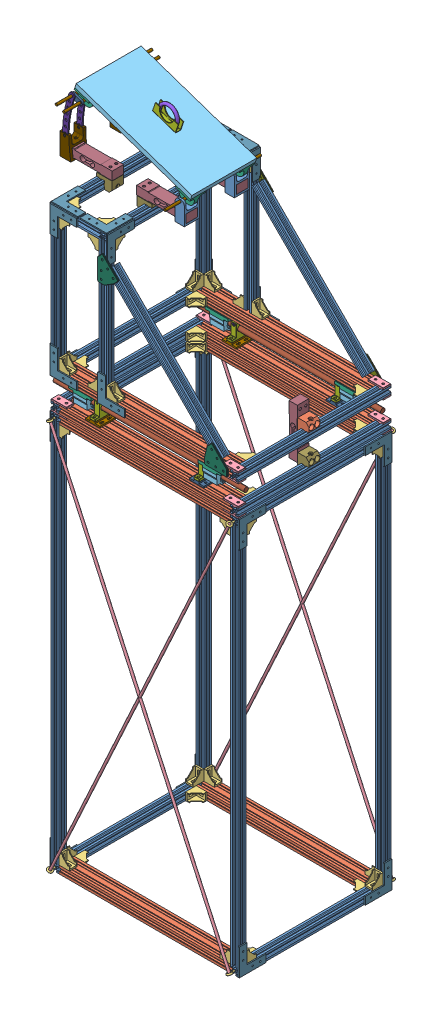
SolidWorks assembly Torre_e_balanca, configuration Valor predeterminado. Lengths in mm.
Overall size (583.29 1742.95 439.8).
205 component instances, 28 part files, 32 mates.
Components (placement in the parent):
- Balança-1: Balança [Valor predeterminado] at (-3.8558 -194.7859 89.5) size (580.29 636.49 408) (flexible)
  - Quadrado_400x490mm-1: Quadrado_400x490mm [Valor predeterminado] at (337.6063 -443.954 467.9915) size (490 20 400)
    - Perfil_20x20mm-3: Perfil_20x20mm [400mm] at (-555.9529 400 -177.9915) x (1 0 0) z (0 -1 0) size (20 400 20)
    - Perfil_20x40mm-2: Perfil_20x40mm [450mm] at (-545.9529 400 -147.9915) x (0 0 -1) z (0 -1 0) size (40 450 20)
    - Perfil_20x40mm-3: Perfil_20x40mm [450mm] at (-545.9529 400 212.0085) x (0 0 -1) z (0 -1 0) size (40 450 20)
    - Perfil_20x20mm-4: Perfil_20x20mm [400mm] at (-85.9529 400 -177.9915) x (1 0 0) z (0 -1 0) size (20 400 20)
    - Cantoneira_interna_20x20mm-1: Cantoneira_interna_20x20mm [Default] at (-95.9529 390 182.0085) x (0 1 0) z (0 0 1) size (20 28 28)
    - Cantoneira_interna_20x20mm-2: Cantoneira_interna_20x20mm [Default] at (-95.9529 410 -137.9915) x (0 -1 0) z (0 0 -1) size (20 28 28)
    - Cantoneira_interna_20x20mm-3: Cantoneira_interna_20x20mm [Default] at (-545.9529 390 -137.9915) x (0 1 0) z (0 0 -1) size (20 28 28)
    - Cantoneira_interna_20x20mm-4: Cantoneira_interna_20x20mm [Default] at (-545.9529 410 182.0085) x (0 -1 0) z (0 0 1) size (20 28 28)
  - Quadrado_400x490mm-2: Quadrado_400x490mm [Valor predeterminado] at (337.6063 -364.954 467.9915) size (490 20 400)
    - Perfil_20x20mm-3: Perfil_20x20mm [400mm] at (-555.9529 400 -177.9915) x (1 0 0) z (0 -1 0) size (20 400 20)
    - Perfil_20x40mm-2: Perfil_20x40mm [450mm] at (-545.9529 400 -147.9915) x (0 0 -1) z (0 -1 0) size (40 450 20)
    - Perfil_20x40mm-3: Perfil_20x40mm [450mm] at (-545.9529 400 212.0085) x (0 0 -1) z (0 -1 0) size (40 450 20)
    - Perfil_20x20mm-4: Perfil_20x20mm [400mm] at (-85.9529 400 -177.9915) x (1 0 0) z (0 -1 0) size (20 400 20)
    - Cantoneira_interna_20x20mm-1: Cantoneira_interna_20x20mm [Default] at (-95.9529 390 182.0085) x (0 1 0) z (0 0 1) size (20 28 28)
    - Cantoneira_interna_20x20mm-2: Cantoneira_interna_20x20mm [Default] at (-95.9529 410 -137.9915) x (0 -1 0) z (0 0 -1) size (20 28 28)
    - Cantoneira_interna_20x20mm-3: Cantoneira_interna_20x20mm [Default] at (-545.9529 390 -137.9915) x (0 1 0) z (0 0 -1) size (20 28 28)
    - Cantoneira_interna_20x20mm-4: Cantoneira_interna_20x20mm [Default] at (-545.9529 410 182.0085) x (0 -1 0) z (0 0 1) size (20 28 28)
  - Cantoneira_Plana_impressa_20x40mm-17: Cantoneira_Plana_impressa_20x40mm [Valor predeterminado] at (241.6534 -33.954 680) x (0 0 -1) z (1 0 0) size (20 6 40)
  - Cantoneira_Plana_impressa_20x40mm-18: Cantoneira_Plana_impressa_20x40mm [Valor predeterminado] at (241.6534 45.046 680) x (0 0 -1) z (1 0 0) size (20 6 40)
  - Cantoneira_Plana_impressa_20x40mm-19: Cantoneira_Plana_impressa_20x40mm [Valor predeterminado] at (241.6534 25.046 680) x (0 0 1) z (1 0 0) size (20 6 40)
  - Cantoneira_Plana_impressa_20x40mm-20: Cantoneira_Plana_impressa_20x40mm [Valor predeterminado] at (241.6534 -53.954 680) x (0 0 1) z (1 0 0) size (20 6 40)
  - Pillow_Block_SC12UU-1: Pillow_Block_SC12UU [Default] at (186.6534 13.046 669) x (0 0 -1) z (1 0 0) size (42 28 36)
  - Adaptador_para_Pillow_Block_SC12UU-2: Adaptador_para_Pillow_Block_SC12UU [Valor predeterminado] at (186.6534 17.046 669) size (60 12.59 42.39)
  - Suporte_SK12-1: Suporte_SK12 [Valor predeterminado] at (110.9034 -7.9702 663.3047) x (0 0 -1) z (1 0 0) size (42 37.6 14)
    - Shaft support SK12-1: Shaft support SK12 [Valor predeterminado] at (-5.6953 6.0163 42) size (42 37.5 14)
    - m4x16-2: m4x16 [Valor predeterminado] at (4.3047 16.0441 42) x (-1 0 0) z (0 0.924225 0.381849) size (20 7 7)
  - Suporte_SK12-3: Suporte_SK12 [Valor predeterminado] at (194.9034 -7.9702 316.6953) x (0 0 1) z (-1 0 0) size (42 37.6 14)
    - Shaft support SK12-1: Shaft support SK12 [Valor predeterminado] at (-5.6953 6.0163 42) size (42 37.5 14)
    - m4x16-2: m4x16 [Valor predeterminado] at (4.3047 16.0441 42) x (-1 0 0) z (0 0.924225 0.381849) size (20 7 7)
  - Suporte_SK12-4: Suporte_SK12 [Valor predeterminado] at (-161.5966 -7.9702 663.3047) x (0 0 -1) z (1 0 0) size (42 37.6 14)
    - Shaft support SK12-1: Shaft support SK12 [Valor predeterminado] at (-5.6953 6.0163 42) size (42 37.5 14)
    - m4x16-2: m4x16 [Valor predeterminado] at (4.3047 16.0441 42) x (-1 0 0) z (0 0.924225 0.381849) size (20 7 7)
  - Suporte_SK12-5: Suporte_SK12 [Valor predeterminado] at (-77.5966 -7.9702 316.6953) x (0 0 1) z (-1 0 0) size (42 37.6 14)
    - Shaft support SK12-1: Shaft support SK12 [Valor predeterminado] at (-5.6953 6.0163 42) size (42 37.5 14)
    - m4x16-2: m4x16 [Valor predeterminado] at (4.3047 16.0441 42) x (-1 0 0) z (0 0.924225 0.381849) size (20 7 7)
  - Adaptador_para_Suporte_SK12_movel-1: Adaptador_para_Suporte_SK12_movel [Valor predeterminado] at (-119.5966 -33.954 669) size (37.5 9 42)
  - Adaptador_para_Suporte_SK12_movel-2: Adaptador_para_Suporte_SK12_movel [Valor predeterminado] at (-119.5966 -33.954 311) size (37.5 9 42)
  - Adaptador_para_Suporte_SK12_fixo-1: Adaptador_para_Suporte_SK12_fixo [Valor predeterminado] at (152.9034 -33.954 669) size (37.5 9 42)
  - Adaptador_para_Suporte_SK12_fixo-3: Adaptador_para_Suporte_SK12_fixo [Valor predeterminado] at (152.9034 -33.954 311) size (37.5 9 42)
  - Eixo_Linear_12mm-1: Eixo_Linear_12mm [500mm] at (11.6534 -1.954 669) x (0 -0.455727 -0.89012) z (1 0 0) size (12 12 500)
  - Pillow_Block_SC12UU-2: Pillow_Block_SC12UU [Default] at (-153.3466 13.046 669) x (0 0 -1) z (1 0 0) size (42 28 36)
  - Pillow_Block_SC12UU-3: Pillow_Block_SC12UU [Default] at (186.6534 13.046 311) x (0 0 1) z (-1 0 0) size (42 28 36)
  - Pillow_Block_SC12UU-4: Pillow_Block_SC12UU [Default] at (-153.3466 13.046 311) x (0 0 1) z (-1 0 0) size (42 28 36)
  - Adaptador_para_Pillow_Block_SC12UU-3: Adaptador_para_Pillow_Block_SC12UU [Valor predeterminado] at (-153.3466 17.046 669) x (-1 0 0) z (0 0 -1) size (60 12.59 42.39)
  - Adaptador_para_Pillow_Block_SC12UU-4: Adaptador_para_Pillow_Block_SC12UU [Valor predeterminado] at (-153.3466 17.046 311) x (-1 0 0) z (0 0 -1) size (60 12.59 42.39)
  - Adaptador_para_Pillow_Block_SC12UU-5: Adaptador_para_Pillow_Block_SC12UU [Valor predeterminado] at (186.6534 17.046 311) size (60 12.59 42.39)
  - Perfil_20x20mm-1: Perfil_20x20mm [350mm] at (-218.3466 45.046 680) size (20 350 20)
  - Perfil_20x20mm-2: Perfil_20x20mm [105mm] at (-103.3466 405.046 680) x (0 1 0) z (0 0 1) size (20 105 20)
  - Perfil_20x20mm-3: Perfil_20x20mm [350mm] at (-93.3466 45.046 680) size (20 350 20)
  - Perfil_20x20mm-7: Perfil_20x20mm [400mm] at (-218.3466 405.046 290) x (0 1 0) z (1 0 0) size (20 400 20)
  - Cantoneira_interna_20x20mm-1: Cantoneira_interna_20x20mm [Default] at (-208.3466 395.046 670) x (0 1 0) z (-1 0 0) size (20 28 28)
  - Cantoneira_interna_20x20mm-2: Cantoneira_interna_20x20mm [Default] at (-208.3466 395.046 670) x (0 0 1) z (0 1 0) size (20 28 28)
  - Cantoneira_interna_20x20mm-3: Cantoneira_interna_20x20mm [Default] at (-208.3466 395.046 670) x (-1 0 0) z (0 0 1) size (20 28 28)
  - Cantoneira_interna_20x20mm-20: Cantoneira_interna_20x20mm [Default] at (-83.3466 45.046 690) x (0 0 -1) z (0 -1 0) size (20 28 28)
  - Suporte_para_Celula_de_Carga_Reforcado-1: Suporte_para_Celula_de_Carga_Reforcado [Valor predeterminado] at (-207.1035 412.2907 570.6317) x (0 0 -1) z (1 0 0) size (30 30 40)
  - Celula_de_Carga_20kg-1: Celula_de_Carga_20kg [Default] at (-252.8466 436.046 570.6317) x (0 0 -1) z (1 0 0) size (30 22 130)
  - Cantoneira_plana_lateral-1: Cantoneira_plana_lateral [Valor predeterminado] at (-228.3466 415.046 693) x (0 0 -1) z (-1 0 0) size (3 70 70)
  - Cantoneira_plana_lateral-9: Cantoneira_plana_lateral [Valor predeterminado] at (-228.3466 418.046 690) x (0 -1 0) z (0 0 1) size (3 70 70)
  - Cantoneira_plana_lateral-10: Cantoneira_plana_lateral [Valor predeterminado] at (-228.3466 415.046 690) x (-1 0 0) z (0 0 1) size (3 70 70)
  - Cantoneira_plana_lateral-19: Cantoneira_plana_lateral [Valor predeterminado] at (-103.3466 25.046 690) x (0 0 1) z (-1 0 0) size (3 70 70)
  - Placa_Lateral_45graus_impressa_esquerda-1: Placa_Lateral_45graus_impressa_esquerda [Default] at (254.8514 25.046 690) x (0 0 1) z (-1 0 0) size (6 57.44 60)
  - Placa_Lateral_45graus_impressa_esquerda-2: Placa_Lateral_45graus_impressa_esquerda [Default] at (-103.3466 383.2441 690) x (0 0 1) z (0.707107 -0.707107 0) size (6 57.44 60)
  - Perfil_20x20mm-10: Perfil_20x20mm [410mm] at (213.6382 52.1171 680) x (0.707107 0.707107 0) z (0 0 1) size (20 410 20)
  - Placa_Lateral_45graus_impressa_direita-1: Placa_Lateral_45graus_impressa_direita [Default] at (254.8514 25.046 286) x (0 0 1) z (-1 0 0) size (6 57.44 60)
  - Placa_Lateral_45graus_impressa_direita-2: Placa_Lateral_45graus_impressa_direita [Default] at (-103.3466 383.2441 286) x (0 0 1) z (0.707107 -0.707107 0) size (6 57.44 60)
  - Montagem_Encaixe_Celula_de_Angulo_Variavel-1: Montagem_Encaixe_Celula_de_Angulo_Variavel [Valor predeterminado] at (-305.8466 447.046 555.6317) x (0 0 1) z (-1 0 0) size (44 158.49 37.27) (flexible)
    - Peça_de_angulo-1: Peça_de_angulo [Default] at (0 43.5356 0.4687) x (1 0 0) z (0 0.144247 0.989542) size (3 125.28 19.4)
    - Peça_Central-1: Peça_Central [Default] at origin size (44 57 28.72)
    - Peça_de_angulo-2: Peça_de_angulo [Default] at (-37 43.5356 0.4687) x (1 0 0) z (0 0.144247 0.989542) size (3 125.28 19.4)
  - Encaixe_Celula_de_Angulo_Fixo-1: Encaixe_Celula_de_Angulo_Fixo [Default] at (-5.8466 447.046 555.6317) x (0 0 -1) z (1 0 0) size (40 57 24)
  - Perfil_20x20mm-11: Perfil_20x20mm [350mm] at (-218.3466 45.046 300) size (20 350 20)
  - Perfil_20x20mm-12: Perfil_20x20mm [350mm] at (-93.3466 45.046 300) size (20 350 20)
  - Perfil_20x20mm-13: Perfil_20x20mm [105mm] at (-103.3466 405.046 300) x (0 1 0) z (0 0 1) size (20 105 20)
  - Eixo_Linear_12mm-3: Eixo_Linear_12mm [500mm] at (11.6534 -1.954 311) x (0 -0.455727 0.89012) z (-1 0 0) size (12 12 500)
  - Cantoneira_interna_20x20mm-21: Cantoneira_interna_20x20mm [Default] at (-83.3466 395.046 670) x (-1 0 0) z (0 0 1) size (20 28 28)
  - Cantoneira_interna_20x20mm-22: Cantoneira_interna_20x20mm [Default] at (-103.3466 415.046 670) x (0 -1 0) z (1 0 0) size (20 28 28)
  - Cantoneira_interna_20x20mm-23: Cantoneira_interna_20x20mm [Default] at (-103.3466 395.046 690) x (0 0 -1) z (0 1 0) size (20 28 28)
  - Cantoneira_interna_20x20mm-24: Cantoneira_interna_20x20mm [Default] at (-228.3466 395.046 310) x (1 0 0) z (0 0 -1) size (20 28 28)
  - Cantoneira_interna_20x20mm-25: Cantoneira_interna_20x20mm [Default] at (-208.3466 415.046 310) x (0 -1 0) z (-1 0 0) size (20 28 28)
  - Cantoneira_interna_20x20mm-26: Cantoneira_interna_20x20mm [Default] at (-208.3466 395.046 290) x (0 0 1) z (0 1 0) size (20 28 28)
  - Cantoneira_interna_20x20mm-27: Cantoneira_interna_20x20mm [Default] at (-103.3466 395.046 310) x (0 1 0) z (1 0 0) size (20 28 28)
  - Cantoneira_interna_20x20mm-28: Cantoneira_interna_20x20mm [Default] at (-103.3466 395.046 310) x (0 0 -1) z (0 1 0) size (20 28 28)
  - Cantoneira_interna_20x20mm-29: Cantoneira_interna_20x20mm [Default] at (-103.3466 395.046 310) x (1 0 0) z (0 0 -1) size (20 28 28)
  - Cantoneira_interna_20x20mm-30: Cantoneira_interna_20x20mm [Default] at (-208.3466 45.046 690) x (0 0 -1) z (0 -1 0) size (20 28 28)
  - Cantoneira_interna_20x20mm-31: Cantoneira_interna_20x20mm [Default] at (-103.3466 45.046 670) x (0 0 1) z (0 -1 0) size (20 28 28)
  - Cantoneira_interna_20x20mm-32: Cantoneira_interna_20x20mm [Default] at (-228.3466 45.046 670) size (20 28 28)
  - Cantoneira_interna_20x20mm-33: Cantoneira_interna_20x20mm [Default] at (-208.3466 45.046 310) x (-1 0 0) z (0 0 -1) size (20 28 28)
  - Cantoneira_interna_20x20mm-34: Cantoneira_interna_20x20mm [Default] at (-208.3466 45.046 310) x (0 0 -1) z (0 -1 0) size (20 28 28)
  - Cantoneira_interna_20x20mm-35: Cantoneira_interna_20x20mm [Default] at (-103.3466 45.046 290) x (0 0 1) z (0 -1 0) size (20 28 28)
  - Cantoneira_interna_20x20mm-36: Cantoneira_interna_20x20mm [Default] at (-83.3466 45.046 310) x (0 0 -1) z (0 -1 0) size (20 28 28)
  - Perfil_20x20mm-14: Perfil_20x20mm [400mm] at (-93.3466 405.046 290) x (0 1 0) z (1 0 0) size (20 400 20)
  - Cantoneira_Plana_impressa_20x40mm-21: Cantoneira_Plana_impressa_20x40mm [Valor predeterminado] at (241.6534 45.046 300) x (0 0 -1) z (1 0 0) size (20 6 40)
  - Cantoneira_Plana_impressa_20x40mm-22: Cantoneira_Plana_impressa_20x40mm [Valor predeterminado] at (241.6534 25.046 300) x (0 0 1) z (1 0 0) size (20 6 40)
  - Cantoneira_Plana_impressa_20x40mm-23: Cantoneira_Plana_impressa_20x40mm [Valor predeterminado] at (-208.3466 25.046 680) x (0 0 -1) z (-1 0 0) size (20 6 40)
  - Cantoneira_Plana_impressa_20x40mm-24: Cantoneira_Plana_impressa_20x40mm [Valor predeterminado] at (-208.3466 25.046 300) x (0 0 -1) z (-1 0 0) size (20 6 40)
  - Cantoneira_Plana_impressa_20x40mm-25: Cantoneira_Plana_impressa_20x40mm [Valor predeterminado] at (-208.3466 -33.954 680) x (0 0 1) z (-1 0 0) size (20 6 40)
  - Cantoneira_Plana_impressa_20x40mm-26: Cantoneira_Plana_impressa_20x40mm [Valor predeterminado] at (-208.3466 -53.954 680) x (0 0 -1) z (-1 0 0) size (20 6 40)
  - Cantoneira_Plana_impressa_20x40mm-27: Cantoneira_Plana_impressa_20x40mm [Valor predeterminado] at (241.6534 -33.954 300) x (0 0 -1) z (1 0 0) size (20 6 40)
  - Cantoneira_Plana_impressa_20x40mm-28: Cantoneira_Plana_impressa_20x40mm [Valor predeterminado] at (241.6534 -53.954 300) x (0 0 1) z (1 0 0) size (20 6 40)
  - Cantoneira_Plana_impressa_20x40mm-29: Cantoneira_Plana_impressa_20x40mm [Valor predeterminado] at (-208.3466 -53.954 300) x (0 0 -1) z (-1 0 0) size (20 6 40)
  - Cantoneira_Plana_impressa_20x40mm-30: Cantoneira_Plana_impressa_20x40mm [Valor predeterminado] at (-208.3466 -33.954 300) x (0 0 1) z (-1 0 0) size (20 6 40)
  - Suporte_para_Celula_de_Carga_Reforcado-2: Suporte_para_Celula_de_Carga_Reforcado [Valor predeterminado] at (-104.5898 412.2907 540.6317) x (0 0 1) z (-1 0 0) size (30 30 40)
  - Suporte_para_Celula_de_Carga_Reforcado-3: Suporte_para_Celula_de_Carga_Reforcado [Valor predeterminado] at (-207.1035 412.2907 439.3683) x (0 0 -1) z (1 0 0) size (30 30 40)
  - Suporte_para_Celula_de_Carga_Reforcado-4: Suporte_para_Celula_de_Carga_Reforcado [Valor predeterminado] at (-104.5898 412.2907 409.3683) x (0 0 1) z (-1 0 0) size (30 30 40)
  - Celula_de_Carga_20kg-2: Celula_de_Carga_20kg [Default] at (-58.8466 436.046 570.6317) x (0 0 -1) z (1 0 0) size (30 22 130)
  - Celula_de_Carga_20kg-3: Celula_de_Carga_20kg [Default] at (-252.8466 436.046 409.3683) x (0 0 1) z (-1 0 0) size (30 22 130)
  - Celula_de_Carga_20kg-4: Celula_de_Carga_20kg [Default] at (-58.8466 436.046 409.3683) x (0 0 1) z (-1 0 0) size (30 22 130)
  - Cantoneira_plana_lateral-20: Cantoneira_plana_lateral [Valor predeterminado] at (-228.3466 415.046 290) x (0 0 -1) z (-1 0 0) size (3 70 70)
  - Cantoneira_plana_lateral-21: Cantoneira_plana_lateral [Valor predeterminado] at (-228.3466 25.046 690) x (0 0 1) z (-1 0 0) size (3 70 70)
  - Cantoneira_plana_lateral-22: Cantoneira_plana_lateral [Valor predeterminado] at (-228.3466 25.046 287) x (0 0 1) z (-1 0 0) size (3 70 70)
  - Cantoneira_plana_lateral-23: Cantoneira_plana_lateral [Valor predeterminado] at (-83.3466 415.046 690) x (0 1 0) z (0 0 1) size (3 70 70)
  - Cantoneira_plana_lateral-24: Cantoneira_plana_lateral [Valor predeterminado] at (-80.3466 415.046 690) x (-1 0 0) z (0 0 1) size (3 70 70)
  - Cantoneira_plana_lateral-25: Cantoneira_plana_lateral [Valor predeterminado] at (-231.3466 415.046 290) x (1 0 0) z (0 0 -1) size (3 70 70)
  - Cantoneira_plana_lateral-26: Cantoneira_plana_lateral [Valor predeterminado] at (-228.3466 415.046 290) x (0 1 0) z (0 0 -1) size (3 70 70)
  - Cantoneira_plana_lateral-27: Cantoneira_plana_lateral [Valor predeterminado] at (-83.3466 415.046 290) x (1 0 0) z (0 0 -1) size (3 70 70)
  - Cantoneira_plana_lateral-28: Cantoneira_plana_lateral [Valor predeterminado] at (-83.3466 418.046 290) x (0 -1 0) z (0 0 -1) size (3 70 70)
  - Cantoneira_plana_lateral-29: Cantoneira_plana_lateral [Valor predeterminado] at (-231.3466 25.046 690) size (3 70 70)
  - Cantoneira_plana_lateral-30: Cantoneira_plana_lateral [Valor predeterminado] at (-228.3466 25.046 290) x (-1 0 0) z (0 0 -1) size (3 70 70)
  - Cantoneira_plana_lateral-31: Cantoneira_plana_lateral [Valor predeterminado] at (-103.3466 25.046 287) x (0 0 1) z (-1 0 0) size (3 70 70)
  - Perfil_20x20mm-15: Perfil_20x20mm [410mm] at (213.6382 52.1171 300) x (0.707107 0.707107 0) z (0 0 1) size (20 410 20)
  - Montagem_Encaixe_Celula_de_Angulo_Variavel-2: Montagem_Encaixe_Celula_de_Angulo_Variavel [Valor predeterminado] at (-305.8466 447.046 424.3683) x (0 0 1) z (-1 0 0) size (44 158.49 37.27) (flexible)
    - Peça_de_angulo-1: Peça_de_angulo [Default] at (0 43.5356 0.4687) x (1 0 0) z (0 0.144247 0.989542) size (3 125.28 19.4)
    - Peça_Central-1: Peça_Central [Default] at origin size (44 57 28.72)
    - Peça_de_angulo-2: Peça_de_angulo [Default] at (-37 43.5356 0.4687) x (1 0 0) z (0 0.144247 0.989542) size (3 125.28 19.4)
  - Encaixe_Celula_de_Angulo_Fixo-4: Encaixe_Celula_de_Angulo_Fixo [Default] at (-5.8466 447.046 424.3683) x (0 0 -1) z (1 0 0) size (40 57 24)
  - Celula_de_Carga_20kg-5: Celula_de_Carga_20kg [Default] at (220.6534 27.546 475) x (0 0 1) z (0 1 0) size (30 22 130)
  - Suporte_para_Celula_de_Carga_Reforcado_ajustavel-2: Suporte_para_Celula_de_Carga_Reforcado_ajustavel [Valor predeterminado] at (244.4087 46.2892 505) x (0 0 -1) z (0 1 0) size (30 30 60)
  - Suporte_para_Celula_de_Carga_Reforcado-11: Suporte_para_Celula_de_Carga_Reforcado [Valor predeterminado] at (244.4087 -32.7108 505) x (0 0 -1) z (0 1 0) size (30 30 40)
- Torre-1: Torre [Valor predeterminado] at (-451.7076 -1438.2292 281.9859) size (496 1040 439.8)
  - Quadrado_400x490mm-1: Quadrado_400x490mm [Valor predeterminado] at (785.4581 775.4893 275.5057) size (490 20 400)
    - Perfil_20x20mm-3: Perfil_20x20mm [400mm] at (-555.9529 400 -177.9915) x (1 0 0) z (0 -1 0) size (20 400 20)
    - Perfil_20x40mm-2: Perfil_20x40mm [450mm] at (-545.9529 400 -147.9915) x (0 0 -1) z (0 -1 0) size (40 450 20)
    - Perfil_20x40mm-3: Perfil_20x40mm [450mm] at (-545.9529 400 212.0085) x (0 0 -1) z (0 -1 0) size (40 450 20)
    - Perfil_20x20mm-4: Perfil_20x20mm [400mm] at (-85.9529 400 -177.9915) x (1 0 0) z (0 -1 0) size (20 400 20)
    - Cantoneira_interna_20x20mm-1: Cantoneira_interna_20x20mm [Default] at (-95.9529 390 182.0085) x (0 1 0) z (0 0 1) size (20 28 28)
    - Cantoneira_interna_20x20mm-2: Cantoneira_interna_20x20mm [Default] at (-95.9529 410 -137.9915) x (0 -1 0) z (0 0 -1) size (20 28 28)
    - Cantoneira_interna_20x20mm-3: Cantoneira_interna_20x20mm [Default] at (-545.9529 390 -137.9915) x (0 1 0) z (0 0 -1) size (20 28 28)
    - Cantoneira_interna_20x20mm-4: Cantoneira_interna_20x20mm [Default] at (-545.9529 410 182.0085) x (0 -1 0) z (0 0 1) size (20 28 28)
  - Quadrado_400x490mm-2: Quadrado_400x490mm [Valor predeterminado] at (785.4581 -244.5107 275.5057) size (490 20 400)
    - Perfil_20x20mm-3: Perfil_20x20mm [400mm] at (-555.9529 400 -177.9915) x (1 0 0) z (0 -1 0) size (20 400 20)
    - Perfil_20x40mm-2: Perfil_20x40mm [450mm] at (-545.9529 400 -147.9915) x (0 0 -1) z (0 -1 0) size (40 450 20)
    - Perfil_20x40mm-3: Perfil_20x40mm [450mm] at (-545.9529 400 212.0085) x (0 0 -1) z (0 -1 0) size (40 450 20)
    - Perfil_20x20mm-4: Perfil_20x20mm [400mm] at (-85.9529 400 -177.9915) x (1 0 0) z (0 -1 0) size (20 400 20)
    - Cantoneira_interna_20x20mm-1: Cantoneira_interna_20x20mm [Default] at (-95.9529 390 182.0085) x (0 1 0) z (0 0 1) size (20 28 28)
    - Cantoneira_interna_20x20mm-2: Cantoneira_interna_20x20mm [Default] at (-95.9529 410 -137.9915) x (0 -1 0) z (0 0 -1) size (20 28 28)
    - Cantoneira_interna_20x20mm-3: Cantoneira_interna_20x20mm [Default] at (-545.9529 390 -137.9915) x (0 1 0) z (0 0 -1) size (20 28 28)
    - Cantoneira_interna_20x20mm-4: Cantoneira_interna_20x20mm [Default] at (-545.9529 410 182.0085) x (0 -1 0) z (0 0 1) size (20 28 28)
  - Perfil_20x20mm-1: Perfil_20x20mm [1000mm] at (699.5052 165.4893 487.5141) size (20 1000 20)
  - Perfil_20x20mm-2: Perfil_20x20mm [1000mm] at (699.5052 1165.4893 107.5141) x (1 0 0) z (0 0 -1) size (20 1000 20)
  - Perfil_20x20mm-3: Perfil_20x20mm [1000mm] at (229.5052 1165.4893 487.5141) x (-1 0 0) z (0 0 1) size (20 1000 20)
  - Perfil_20x20mm-4: Perfil_20x20mm [1000mm] at (229.5052 165.4893 107.5141) x (-1 0 0) z (0 0 -1) size (20 1000 20)
  - Cantoneira_interna_20x20mm-1: Cantoneira_interna_20x20mm [Default] at (689.5052 165.4893 477.5141) size (20 28 28)
  - Cantoneira_interna_20x20mm-2: Cantoneira_interna_20x20mm [Default] at (689.5052 165.4893 477.5141) x (0 0 1) z (0 -1 0) size (20 28 28)
  - Cantoneira_plana_lateral-3: Cantoneira_plana_lateral [Valor predeterminado] at (709.5052 145.4893 497.5141) size (3 70 70)
  - Cantoneira_interna_20x20mm-3: Cantoneira_interna_20x20mm [Default] at (689.5052 165.4893 97.5141) x (0 0 1) z (0 -1 0) size (20 28 28)
  - Cantoneira_interna_20x20mm-4: Cantoneira_interna_20x20mm [Default] at (709.5052 165.4893 117.5141) x (-1 0 0) z (0 0 -1) size (20 28 28)
  - Cantoneira_interna_20x20mm-5: Cantoneira_interna_20x20mm [Default] at (239.5052 165.4893 497.5141) x (0 0 -1) z (0 -1 0) size (20 28 28)
  - Cantoneira_interna_20x20mm-6: Cantoneira_interna_20x20mm [Default] at (219.5052 165.4893 477.5141) size (20 28 28)
  - Cantoneira_interna_20x20mm-7: Cantoneira_interna_20x20mm [Default] at (239.5052 165.4893 117.5141) x (-1 0 0) z (0 0 -1) size (20 28 28)
  - Cantoneira_interna_20x20mm-8: Cantoneira_interna_20x20mm [Default] at (239.5052 165.4893 117.5141) x (0 0 -1) z (0 -1 0) size (20 28 28)
  - Cantoneira_interna_20x20mm-9: Cantoneira_interna_20x20mm [Default] at (709.5052 1165.4893 477.5141) x (-1 0 0) z (0 0 1) size (20 28 28)
  - Cantoneira_interna_20x20mm-10: Cantoneira_interna_20x20mm [Default] at (689.5052 1165.4893 497.5141) x (0 0 -1) z (0 1 0) size (20 28 28)
  - Cantoneira_interna_20x20mm-11: Cantoneira_interna_20x20mm [Default] at (689.5052 1165.4893 117.5141) x (0 0 -1) z (0 1 0) size (20 28 28)
  - Cantoneira_interna_20x20mm-12: Cantoneira_interna_20x20mm [Default] at (689.5052 1165.4893 117.5141) x (1 0 0) z (0 0 -1) size (20 28 28)
  - Cantoneira_interna_20x20mm-13: Cantoneira_interna_20x20mm [Default] at (239.5052 1165.4893 477.5141) x (0 0 1) z (0 1 0) size (20 28 28)
  - Cantoneira_interna_20x20mm-14: Cantoneira_interna_20x20mm [Default] at (239.5052 1165.4893 477.5141) x (-1 0 0) z (0 0 1) size (20 28 28)
  - Cantoneira_interna_20x20mm-15: Cantoneira_interna_20x20mm [Default] at (239.5052 1165.4893 97.5141) x (0 0 1) z (0 1 0) size (20 28 28)
  - Cantoneira_interna_20x20mm-16: Cantoneira_interna_20x20mm [Default] at (219.5052 1165.4893 117.5141) x (1 0 0) z (0 0 -1) size (20 28 28)
  - Cantoneira_plana_lateral-6: Cantoneira_plana_lateral [Valor predeterminado] at (712.5052 145.4893 97.5141) x (-1 0 0) z (0 0 -1) size (3 70 70)
  - Cantoneira_plana_lateral-8: Cantoneira_plana_lateral [Valor predeterminado] at (216.5052 145.4893 497.5141) size (3 70 70)
  - Cantoneira_plana_lateral-10: Cantoneira_plana_lateral [Valor predeterminado] at (219.5052 145.4893 97.5141) x (-1 0 0) z (0 0 -1) size (3 70 70)
  - Cantoneira_plana_lateral-12: Cantoneira_plana_lateral [Valor predeterminado] at (712.5052 1185.4893 497.5141) x (-1 0 0) z (0 0 1) size (3 70 70)
  - Cantoneira_plana_lateral-13: Cantoneira_plana_lateral [Valor predeterminado] at (709.5052 1185.4893 97.5141) x (1 0 0) z (0 0 -1) size (3 70 70)
  - Cantoneira_plana_lateral-15: Cantoneira_plana_lateral [Valor predeterminado] at (219.5052 1185.4893 497.5141) x (-1 0 0) z (0 0 1) size (3 70 70)
  - Cantoneira_plana_lateral-17: Cantoneira_plana_lateral [Valor predeterminado] at (216.5052 1185.4893 97.5141) x (1 0 0) z (0 0 -1) size (3 70 70)
  - Parafuso_Olhal_30mm-1: Parafuso_Olhal_30mm [Valor predeterminado] at (699.5052 155.4893 510.2646) x (-0.418493 0.90822 0) z (0.90822 0.418493 0) size (4.3 42.15 14.3)
  - Cabo_de_aco-1: Cabo_de_aco [Valor predeterminado] at (699.8354 154.7727 510.2646) x (-0.296683 -0.136707 0.94514) z (-0.858395 -0.395535 -0.326665) size (6 1124 6)
  - Parafuso_Olhal_30mm-2: Parafuso_Olhal_30mm [Valor predeterminado] at (699.5052 155.4893 84.7636) x (0.418493 -0.90822 0) z (0.90822 0.418493 0) size (4.3 42.15 14.3)
  - Parafuso_Olhal_30mm-3: Parafuso_Olhal_30mm [Valor predeterminado] at (229.5052 155.4893 510.2646) x (-0.418493 -0.90822 0) z (-0.90822 0.418493 0) size (4.3 42.15 14.3)
  - Parafuso_Olhal_30mm-4: Parafuso_Olhal_30mm [Valor predeterminado] at (229.5052 155.4893 84.7636) x (0.418493 0.90822 0) z (-0.90822 0.418493 0) size (4.3 42.15 14.3)
  - Parafuso_Olhal_30mm-5: Parafuso_Olhal_30mm [Valor predeterminado] at (699.5052 1175.4893 510.2646) x (0.418493 0.90822 0) z (0.90822 -0.418493 0) size (4.3 42.15 14.3)
  - Parafuso_Olhal_30mm-6: Parafuso_Olhal_30mm [Valor predeterminado] at (699.5052 1175.4893 84.7636) x (-0.418493 -0.90822 0) z (0.90822 -0.418493 0) size (4.3 42.15 14.3)
  - Parafuso_Olhal_30mm-7: Parafuso_Olhal_30mm [Valor predeterminado] at (229.5052 1175.4893 84.7636) x (-0.418493 0.90822 0) z (-0.90822 -0.418493 0) size (4.3 42.15 14.3)
  - Parafuso_Olhal_30mm-8: Parafuso_Olhal_30mm [Valor predeterminado] at (229.5052 1175.4893 510.2646) x (0.418493 -0.90822 0) z (-0.90822 -0.418493 0) size (4.3 42.15 14.3)
  - Cabo_de_aco-2: Cabo_de_aco [Valor predeterminado] at (699.8354 154.7727 84.7636) x (-0.296683 -0.136707 -0.94514) z (0.858395 0.395535 -0.326665) size (6 1124 6)
  - Cabo_de_aco-3: Cabo_de_aco [Valor predeterminado] at (229.175 154.7727 510.2646) x (0.296683 -0.136707 0.94514) z (-0.858395 0.395535 0.326665) size (6 1124 6)
  - Cabo_de_aco-4: Cabo_de_aco [Valor predeterminado] at (229.175 154.7727 84.7636) x (0.296683 -0.136707 -0.94514) z (0.858395 -0.395535 0.326665) size (6 1124 6)
- Montagem_Placa_de_Calibracao-2: Montagem_Placa_de_Calibracao [Valor predeterminado] at (-143.1195 374.1988 219.5) x (0.947187 -0.320681 0) z (0 0 1) size (320 91.03 170)
  - Placa-1: Placa [Valor predeterminado] at (18.0321 -23.8402 360) size (320 12 170)
  - Encaixe_Placa_de_Calibracao-1: Encaixe_Placa_de_Calibracao [Default] at (158.0321 -23.8402 295) x (0 0 -1) z (-1 0 0) size (40 35 40)
  - Encaixe_Placa_de_Calibracao-2: Encaixe_Placa_de_Calibracao [Default] at (158.0321 -23.8402 425) x (0 0 -1) z (-1 0 0) size (40 35 40)
  - Encaixe_Placa_de_Calibracao-3: Encaixe_Placa_de_Calibracao [Default] at (-121.9679 -23.8402 295) x (0 0 -1) z (-1 0 0) size (40 35 40)
  - Encaixe_Placa_de_Calibracao-4: Encaixe_Placa_de_Calibracao [Default] at (-121.9679 -23.8402 425) x (0 0 -1) z (-1 0 0) size (40 35 40)
  - Abracadeira_Grampo_U_Placa_de_Calibracao_Base-1: Abracadeira_Grampo_U_Placa_de_Calibracao_Base [Valor predeterminado] at (-13.4679 13.1598 352.5) x (0 0 1) z (1 0 0) size (15 25 63)
  - Abracadeira_Grampo_U_Placa_de_Calibracao_Argola-1: Abracadeira_Grampo_U_Placa_de_Calibracao_Argola [Valor predeterminado] at (18.0321 5.1388 360) x (0 -1 0) z (0 0 1) size (77.62 54.23 8.06)
- Vareta6mm-1: Vareta6mm [Valor predeterminado] at (-9.0957 277.2601 704.5) x (0 0 -1) z (1 0 0) size (250 6 6)
- Vareta6mm-2: Vareta6mm [Valor predeterminado] at (-274.3081 367.0508 704.5) x (0 0 -1) z (-0.181208 -0.983445 0) size (250 6 6)
- Vareta6mm-3: Vareta6mm [Valor predeterminado] at (-309.4887 265.9393 704.5) x (0 0 -1) z (-0.316917 0.948453 0) size (250 6 6) (hidden)
- Vareta6mm-4: Vareta6mm [Valor predeterminado] at (-293.634 374.1251 704.5) x (0 0 -1) z (-0.999567 0.029426 0) size (250 6 6)
- Extensor-3: Extensor [Valor predeterminado] at (-294.4368 374.4189 662.1317) x (0 0 -1) z (0.939062 -0.343747 0) size (5 12 32.58)
- Extensor-4: Extensor [Valor predeterminado] at (-294.4368 374.4189 633.1317) x (0 0 -1) z (0.939062 -0.343747 0) size (5 12 32.58)
- Extensor-5: Extensor [Valor predeterminado] at (-273.5053 366.7569 496.8683) x (0 0 1) z (-0.939062 0.343747 0) size (5 12 32.58)
- Extensor-6: Extensor [Valor predeterminado] at (-273.5053 366.7569 525.8683) x (0 0 1) z (-0.939062 0.343747 0) size (5 12 32.58)
Mates (geometry in assembly coordinates):
- Coincidente1: coincident: plane of Balança-1/Quadrado_400x490mm-1/Perfil_20x40mm-3 through (237.7976 -242.7399 779.5) normal (0 0 1); plane of ? through (237.7976 -305.3705 779.5) normal (0 0 1)
- Coincidente2: coincident: plane of Balança-1/Quadrado_400x490mm-1/Perfil_20x20mm-3 through (-232.2024 -238.7399 779.5) normal (-1 0 0); plane of ? through (-232.2024 -315.3705 779.5) normal (-1 0 0)
- Coincidente4: coincident anti-aligned: plane of Balança-1/Cantoneira_Plana_impressa_20x40mm-26 through (-212.2024 -252.7399 769.5) normal (0 -1 0); plane of Torre-1/Quadrado_400x490mm-1/Perfil_20x20mm-3 through (-222.2024 -252.7399 779.5) normal (0 1 0)
- Coincidente5: coincident aligned: plane of Balança-1/Quadrado_400x490mm-1/Perfil_20x40mm-3 through (237.7976 -242.7399 779.5) normal (0 0 1); plane of Torre-1/Quadrado_400x490mm-1/Perfil_20x40mm-3 through (237.7976 -252.7399 779.5) normal (0 0 1)
- Coincidente6: coincident aligned: plane of Balança-1/Quadrado_400x490mm-1/Perfil_20x20mm-3 through (-232.2024 -238.7399 779.5) normal (-1 0 0); plane of Torre-1/Quadrado_400x490mm-1/Perfil_20x20mm-3 through (-232.2024 -262.7399 779.5) normal (-1 0 0)
- Coincidente7: coincident anti-aligned: plane of Balança-1/Cantoneira_Plana_impressa_20x40mm-26 through (-212.2024 -252.7399 769.5) normal (0 -1 0); plane of Torre-1/Quadrado_400x490mm-1/Perfil_20x20mm-3 through (-222.2024 -252.7399 779.5) normal (0 1 0)
- No local1: in place: plane of ? through (0 0 0) normal (0 1 0); moOrthogonalPlaneRef_w of ? through (0 0 0) normal (0 0 -1); line of ? through (55 -55 0) axis (0 0 1); unknown of ?
- Coincidente8: coincident aligned: plane of ?; plane of assembly
- Coincidente9: coincident aligned: plane of ? through (0 0 0) normal (0 0 -1)
- Coincidente10: coincident anti-aligned: line of ? through (55 -55 0) axis (0 0 1)
- Simétrico1: symmetric aligned: plane of Balança-1 through (-3.8558 -194.7859 579.5) normal (0 0 1); plane of ? through (-331.5364 272.4358 504.5) normal (0 0 1); plane of ? through (-331.5364 272.4358 654.5) normal (0 0 -1)
- Concêntrico4: concentric anti-aligned: cylinder of ? through (-309.7024 277.2601 679.5) axis (0 0 -1) radius 4; cylinder of ? through (-309.7024 277.2601 379.5) axis (0 0 1) radius 4
- Concêntrico6: concentric anti-aligned: cylinder of ? through (-9.0957 277.2601 379.5) axis (0 0 1) radius 3; cylinder of Montagem_Placa_de_Calibracao-2/Encaixe_Placa_de_Calibracao-2 through (-9.0957 277.2601 664.5) axis (0 0 -1) radius 3
- Simétrico4: symmetric aligned: plane of Montagem_Placa_de_Calibracao-2/Placa-1 through (-281.3867 408.5103 494.5) normal (0 0 -1); plane of Montagem_Placa_de_Calibracao-2/Placa-1 through (-281.3867 408.5103 664.5) normal (0 0 1); plane of assembly through (0 0 579.5) normal (0 0 1)
- Concêntrico11: concentric anti-aligned: cylinder of Montagem_Placa_de_Calibracao-2/Encaixe_Placa_de_Calibracao-2 through (-9.0957 277.2601 664.5) axis (0 0 -1) radius 3; cylinder of Vareta6mm-1 through (-9.0957 277.2601 454.5) axis (0 0 1) radius 3
- Simétrico5: symmetric aligned: plane of Vareta6mm-1 through (-9.0957 277.2601 704.5) normal (0 0 1); plane of Vareta6mm-1 through (-9.0957 277.2601 454.5) normal (0 0 -1); plane of assembly through (0 0 579.5) normal (0 0 1)
- Concêntrico16: concentric aligned: circle of Balança-1/Encaixe_Celula_de_Angulo_Fixo-1; circle of Montagem_Placa_de_Calibracao-2/Encaixe_Placa_de_Calibracao-2
- Concêntrico17: concentric anti-aligned: cylinder of Montagem_Placa_de_Calibracao-2/Encaixe_Placa_de_Calibracao-4 through (-274.3081 367.0508 664.5) axis (0 0 -1) radius 3; cylinder of Vareta6mm-2 through (-274.3081 367.0508 454.5) axis (0 0 1) radius 3
- Coincidente8: coincident aligned: plane of Vareta6mm-1 through (-9.0957 277.2601 704.5) normal (0 0 1); plane of Vareta6mm-2 through (-274.3081 367.0508 704.5) normal (0 0 1)
- Coincidente9: coincident aligned: plane of Vareta6mm-2 through (-274.3081 367.0508 704.5) normal (0 0 1); plane of Vareta6mm-3 through (-309.4887 265.9393 704.5) normal (0 0 1)
- Concêntrico18: concentric aligned: cylinder of Balança-1/Montagem_Encaixe_Celula_de_Angulo_Variavel-1/Peça_de_angulo-1 through (-309.4887 265.9393 662.1317) axis (0 0 1) radius 3; cylinder of Vareta6mm-3 through (-309.4887 265.9393 454.5) axis (0 0 1) radius 3
- Concêntrico21: concentric aligned: cylinder of Balança-1/Montagem_Encaixe_Celula_de_Angulo_Variavel-1/Peça_de_angulo-1 through (-293.634 374.1251 662.1317) axis (0 0 1) radius 3; cylinder of Vareta6mm-4 through (-293.634 374.1251 454.5) axis (0 0 1) radius 3
- Coincidente11: coincident aligned: plane of Vareta6mm-2 through (-274.3081 367.0508 704.5) normal (0 0 1); plane of Vareta6mm-4 through (-293.634 374.1251 704.5) normal (0 0 1)
- Concêntrico22: concentric aligned: cylinder of ? through (-289.7325 384.885 678.6007) axis (0 0 1) radius 3; cylinder of Vareta6mm-4 through (-289.7325 384.885 454.5) axis (0 0 1) radius 3
- Concêntrico24: concentric aligned: cylinder of Vareta6mm-2 through (-255.0764 411.0266 454.5) axis (0 0 1) radius 3; cylinder of ? through (-255.0764 411.0266 678.6007) axis (0 0 1) radius 3
- Concêntrico25: concentric aligned: cylinder of Vareta6mm-4 through (-293.634 374.1251 454.5) axis (0 0 1) radius 3; cylinder of Extensor-3 through (-293.634 374.1251 657.1317) axis (0 0 1) radius 3
- Concêntrico26: concentric aligned: cylinder of Vareta6mm-2 through (-274.3081 367.0508 454.5) axis (0 0 1) radius 3; cylinder of Extensor-3 through (-274.3081 367.0508 657.1317) axis (0 0 1) radius 3
- Concêntrico29: concentric aligned: cylinder of Vareta6mm-4 through (-293.634 374.1251 454.5) axis (0 0 1) radius 3; cylinder of Extensor-4 through (-293.634 374.1251 628.1317) axis (0 0 1) radius 3
- Concêntrico30: concentric aligned: cylinder of Vareta6mm-2 through (-274.3081 367.0508 454.5) axis (0 0 1) radius 3; cylinder of Extensor-4 through (-274.3081 367.0508 628.1317) axis (0 0 1) radius 3
- Coincidente12: coincident anti-aligned: plane of Balança-1/Montagem_Encaixe_Celula_de_Angulo_Variavel-1/Peça_de_angulo-2 through (-310.1711 295.7956 628.1317) normal (0 0 1); plane of Extensor-4 through (-274.3081 367.0508 628.1317) normal (0 0 -1)
- Coincidente13: coincident anti-aligned: plane of Balança-1/Montagem_Encaixe_Celula_de_Angulo_Variavel-1/Peça_de_angulo-1 through (-310.1711 295.7956 662.1317) normal (0 0 -1); plane of Extensor-3 through (-274.3081 367.0508 662.1317) normal (0 0 1)
- Largura1: width anti-aligned: plane of Balança-1/Montagem_Encaixe_Celula_de_Angulo_Variavel-1/Peça_de_angulo-1 through (-310.1711 295.7956 662.1317) normal (0 0 -1); plane of Balança-1/Montagem_Encaixe_Celula_de_Angulo_Variavel-2/Peça_de_angulo-2 through (-310.1711 295.7956 496.8683) normal (0 0 1); plane of Montagem_Placa_de_Calibracao-2/Encaixe_Placa_de_Calibracao-3 through (-296.4587 363.9925 519.5) normal (0 0 1); plane of Montagem_Placa_de_Calibracao-2/Encaixe_Placa_de_Calibracao-4 through (-296.4587 363.9925 639.5) normal (0 0 -1)
